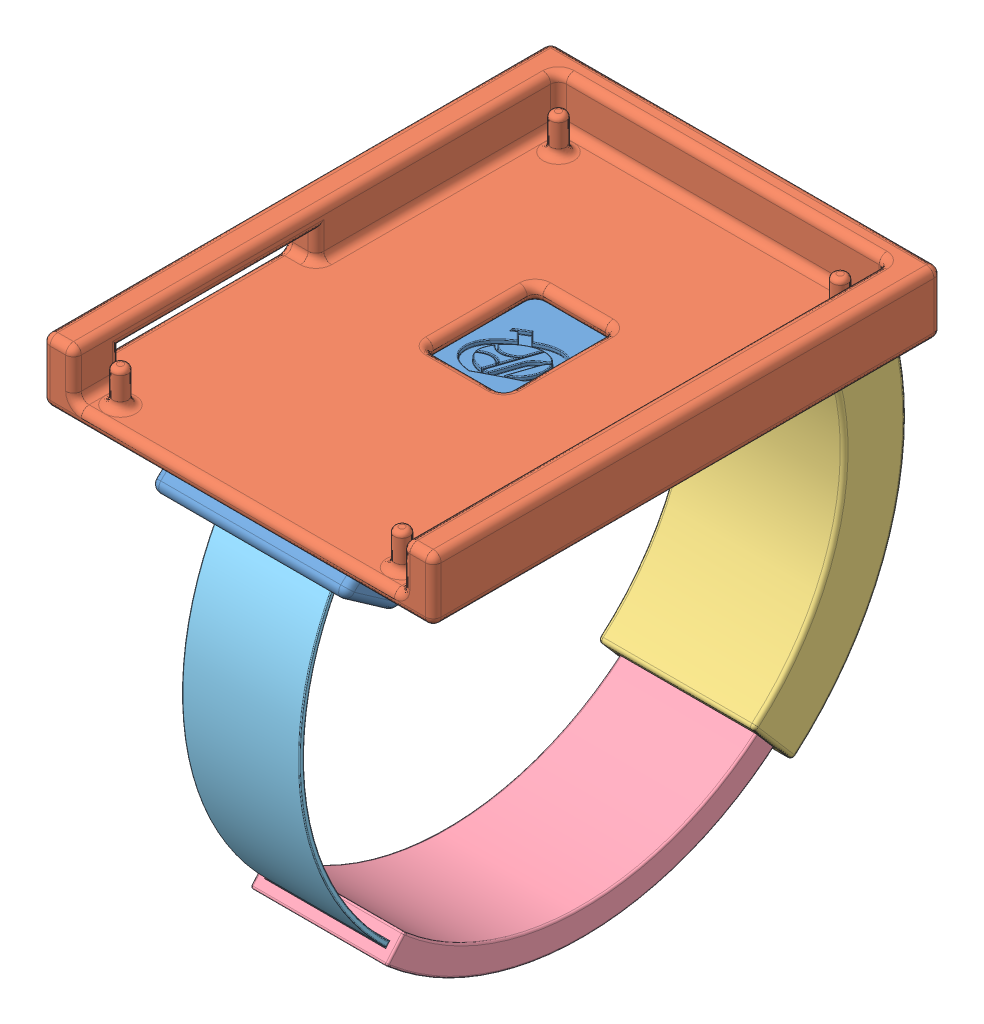
SolidWorks assembly WatchAssembly, configuration Default. Lengths in mm.
Overall size (50 71.49 80.72).
5 component instances, 5 part files, 19 mates.
Components (placement in the parent):
- Connector-1: Connector [Default] at (-23.0636 4.5887 3.1293) size (25 8.46 51.1)
- TopPiece-1: TopPiece [Default] at (-23.0636 12.5887 3.1293) x (-1 0 0) z (0 0 -1) size (50 15 65)
- LeftBand-1: LeftBand [Default] at (-23.0636 8.5887 -14.3707) x (0 0 -1) z (1 0 0) size (30.02 52.25 20.09)
- Intermediate Band-1: Intermediate Band [Default] at (-22.7563 -23.6599 -16.842) x (0 -0.988746 -0.149603) z (1 0 0) size (15.71 50.07 17.54)
- RightBand-1: RightBand [Default] at (-23.0063 -31.849 14.2206) x (0 -0.236372 0.971663) z (1 0 0) size (13.15 47.71 15.2)
Mates (geometry in assembly coordinates):
- Coincident1: coincident: plane of Connector-1 through (-14.0636 5.5887 3.1293) normal (0 1 0); circle of TopPiece-1
- Coincident2: coincident: plane of Connector-1 through (-32.0636 5.5887 3.1293) normal (0 1 0); circle of TopPiece-1
- Coincident3: coincident: plane of Connector-1 through (-23.0636 12.5887 3.1293) normal (0 1 0); plane of TopPiece-1 through (-23.0636 12.5887 3.1293) normal (0 -1 0)
- Coincident5: coincident: plane of Connector-1 through (-23.0636 5.5887 3.1293) normal (0 1 0); plane of TopPiece-1 through (-23.0636 5.5887 3.1293) normal (0 -1 0)
- Concentric1: concentric: circle of Connector-1; circle of TopPiece-1
- Concentric2: concentric: circle of Connector-1; circle of TopPiece-1
- Coincident6: coincident: plane of Connector-1 through (-35.5636 12.5887 -14.3707) normal (0 0 -1); plane of LeftBand-1 through (-23.0636 8.5887 -14.3707) normal (0 0 1)
- Coincident7: coincident: plane of Connector-1 through (-10.5636 5.5887 -10.3707) normal (0 1 0); plane of LeftBand-1 through (-33.0636 5.5887 -37.3899) normal (0 -1 0)
- Coincident8: coincident: plane of Connector-1 through (-35.5636 5.5887 -10.3707) normal (0 1 0); plane of LeftBand-1 through (-33.0636 5.5887 -37.3899) normal (0 -1 0)
- Parallel3: parallel: plane of Connector-1 through (-23.0636 12.5887 3.1293) normal (0 1 0); plane of LeftBand-1 through (-33.0636 8.5887 -37.3899) normal (0 1 0)
- Parallel4: parallel: plane of Connector-1 through (-10.5636 12.5887 -14.3707) normal (1 0 0); plane of LeftBand-1 through (-13.0636 -33.5259 -18.0994) normal (1 0 0)
- Coincident12: coincident: plane of Connector-1 through (-14.5636 7.5887 -7.3707) normal (-1 0 0); plane of LeftBand-1 through (-14.5636 7.2887 -7.3707) normal (1 0 0)
- Parallel7: parallel: cylinder of LeftBand-1 through (-23.0636 -8.8932 3.1293) axis (1 0 0) radius 40.5182; cylinder of Intermediate Band-1 through (-22.7563 -8.9722 3.0612) axis (1 0 0) radius 38.0172
- Parallel8: parallel: cylinder of LeftBand-1 through (-23.0636 -8.8932 3.1293) axis (1 0 0) radius 32.5182; cylinder of Intermediate Band-1 through (-22.7563 -8.9722 3.0612) axis (1 0 0) radius 34.5172
- Coincident15: coincident: line of LeftBand-1 through (-32.0636 -38.071 -22.0164) axis (1 0 0); plane of Intermediate Band-1 through (-22.7563 -27.2428 -12.6845) normal (0 -0.652826 0.757508)
- Coincident16: coincident: line of LeftBand-1 through (-14.0636 -35.041 -19.4051) axis (-1 0 0); plane of Intermediate Band-1 through (-22.7563 -27.2428 -12.6845) normal (0 -0.652826 0.757508)
- Parallel9: parallel: cylinder of Intermediate Band-1 through (-22.7563 -8.9722 3.0612) axis (1 0 0) radius 34.5172; cylinder of RightBand-1 through (-23.0063 -10.7261 1.3487) axis (1 0 0) radius 36.4682
- Coincident17: coincident: line of Intermediate Band-1 through (-30.5063 -36.2317 26.3715) axis (1 0 0); cylinder of RightBand-1 through (-23.0063 -36.3272 26.2989) axis (1 0 0) radius 0.12
- Coincident18: coincident: plane of Intermediate Band-1 through (-30.5063 -35.2057 25.4942) normal (1 0 0); plane of RightBand-1 through (-30.5063 10.1396 30.5231) normal (-1 0 0)
